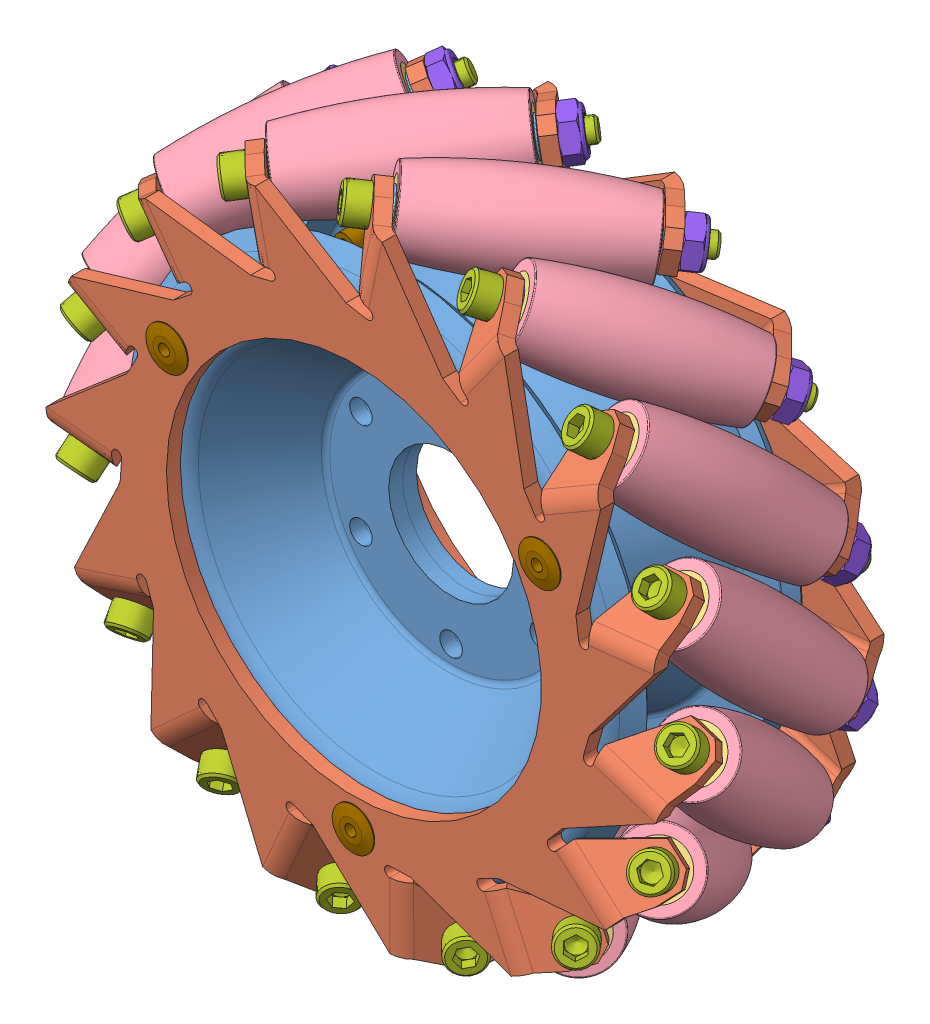
SolidWorks assembly am-3479L+6+SR+Mecanum+Left, configuration Default. Lengths in mm.
Overall size (158.3 158.04 52.39).
130 component instances, 9 part files, 0 mates.
Components (placement in the parent):
- ip-3479_hub-1: ip-3479_hub [Default] x (0 0 1) z (1 0 0) size (22.23 118.71 118.71)
- ip-3479_hub-2: ip-3479_hub [Default] x (0 0 -1) z (-1 0 0) size (22.23 118.71 118.71)
- am-0676a Left Plate HD-1: am-0676a Left Plate HD [Default] at (0 0 23.114) x (-0.999437 -0.033548 0) z (0 0 1) size (146.64 146.22 13.05)
- am-0676a Left Plate HD-2: am-0676a Left Plate HD [Default] at (0 0 -23.114) x (0.99946 -0.032864 0) z (0 0 -1) size (146.64 146.22 13.05)
- am-3479_roller-1: am-3479_roller [Default] at (-1.2868 -63.2825 -0.1615) x (-0.034273 0.998836 0.033931) z (0.706278 0.048228 -0.70629) size (19.48 44.35 19.48)
  - am-3698_core PC-1: am-3698_core PC [Default] at (-2.9239 1.0394 0.8367) size (14.92 43.18 14.92)
  - am-3698_skin TPU v2-1: am-3698_skin TPU v2 [Default] at (-2.9239 22.6294 0.8367) x (1 0 0) z (0 1 0) size (19.48 19.48 43.18)
  - am-0603 MBC Bushing MU04TH04-1: am-0603 MBC Bushing MU04TH04 [Default] at (-2.9239 -20.9316 0.8367) x (0 1 0) z (0 0 1) size (6.36 7.94 7.94)
  - am-0603 MBC Bushing MU04TH04-2: am-0603 MBC Bushing MU04TH04 [Default] at (-2.9239 16.6604 0.8367) x (0 1 0) z (-0.707574 0 0.70664) size (6.36 7.94 7.94)
  - am-0701a 6IN SR Roller Axle-1: am-0701a 6IN SR Roller Axle [Default] at (-2.9239 23.2136 0.8367) x (0 -1 0) z (0 0 1) size (44.35 6.35 6.35)
- 10-32x2250_shcs_HX-SHCS 0.19-32x1.375x1-C-1: 10-32x2250_shcs_HX-SHCS 0.19-32x1.375x1-C [Default] at (21.4977 -66.155 21.2417) x (-0.707105 -0.000242 -0.707109) z (0.143048 -0.979373 -0.142712) size (61.98 7.94 7.94)
- 10-32 Nylock Jam Nut_90633A411-1: 10-32 Nylock Jam Nut_90633A411 [Default] at (-17.791 -66.1685 -18.0472) x (0.176781 0.968184 -0.177112) z (-0.684654 0.25024 0.684564) size (9.53 4.55 11)
- 10-32 Nylock Jam Nut_90633A411-2: 10-32 Nylock Jam Nut_90633A411 [Default] at (-43.166 -53.2117 -18.0472) x (0.555294 0.812576 -0.177112) z (-0.523681 0.50708 0.684564) size (9.53 4.55 11)
- 10-32 Nylock Jam Nut_90633A411-3: 10-32 Nylock Jam Nut_90633A411 [Default] at (-61.0773 -31.0541 -18.0472) x (0.837791 0.516467 -0.177112) z (-0.272158 0.676241 0.684564) size (9.53 4.55 11)
- 10-32 Nylock Jam Nut_90633A411-4: 10-32 Nylock Jam Nut_90633A411 [Default] at (-68.4277 -3.527 -18.0472) x (0.975426 0.131056 -0.177112) z (0.026423 0.728473 0.684564) size (9.53 4.55 11)
- 10-32 Nylock Jam Nut_90633A411-5: 10-32 Nylock Jam Nut_90633A411 [Default] at (-63.9463 24.61 -18.0472) x (0.944401 -0.277016 -0.177112) z (0.320435 0.654747 0.684564) size (9.53 4.55 11)
- 10-32 Nylock Jam Nut_90633A411-6: 10-32 Nylock Jam Nut_90633A411 [Default] at (-48.4081 48.4917 -18.0472) x (0.750081 -0.637189 -0.177112) z (0.559041 0.467808 0.684564) size (9.53 4.55 11)
- 10-32 Nylock Jam Nut_90633A411-7: 10-32 Nylock Jam Nut_90633A411 [Default] at (-24.4997 63.9887 -18.0472) x (0.426065 -0.887187 -0.177112) z (0.700984 0.199981 0.684564) size (9.53 4.55 11)
- 10-32 Nylock Jam Nut_90633A411-8: 10-32 Nylock Jam Nut_90633A411 [Default] at (3.645 68.4215 -18.0472) x (0.028379 -0.983782 -0.177112) z (0.721721 -0.102424 0.684564) size (9.53 4.55 11)
- 10-32 Nylock Jam Nut_90633A411-9: 10-32 Nylock Jam Nut_90633A411 [Default] at (31.1594 61.0236 -18.0472) x (-0.374215 -0.910272 -0.177112) z (0.617665 -0.387119 0.684564) size (9.53 4.55 11)
- 10-32 Nylock Jam Nut_90633A411-10: 10-32 Nylock Jam Nut_90633A411 [Default] at (53.2861 43.0742 -18.0472) x (-0.712103 -0.679368 -0.177112) z (0.40681 -0.604878 0.684564) size (9.53 4.55 11)
- 10-32 Nylock Jam Nut_90633A411-11: 10-32 Nylock Jam Nut_90633A411 [Default] at (66.1991 17.6768 -18.0472) x (-0.926862 -0.330995 -0.177112) z (0.125613 -0.718048 0.684564) size (9.53 4.55 11)
- 10-32 Nylock Jam Nut_90633A411-12: 10-32 Nylock Jam Nut_90633A411 [Default] at (67.6657 -10.777 -18.0472) x (-0.981359 0.07461 -0.177112) z (-0.177303 -0.707061 0.684564) size (9.53 4.55 11)
- 10-32 Nylock Jam Nut_90633A411-13: 10-32 Nylock Jam Nut_90633A411 [Default] at (57.4323 -37.3674 -18.0472) x (-0.866169 0.467314 -0.177112) z (-0.449562 -0.573817 0.684564) size (9.53 4.55 11)
- 10-32 Nylock Jam Nut_90633A411-14: 10-32 Nylock Jam Nut_90633A411 [Default] at (37.2683 -57.4966 -18.0472) x (-0.601211 0.779216 -0.177112) z (-0.644088 -0.341354 0.684564) size (9.53 4.55 11)
- 10-32 Nylock Jam Nut_90633A411-15: 10-32 Nylock Jam Nut_90633A411 [Default] at (10.6603 -67.6842 -18.0472) x (-0.232298 0.956383 -0.177112) z (-0.727245 -0.049868 0.684564) size (9.53 4.55 11)
- 10-32x2250_shcs_HX-SHCS 0.19-32x1.375x1-C-2: 10-32x2250_shcs_HX-SHCS 0.19-32x1.375x1-C [Default] at (-7.2685 -69.1795 21.2417) x (-0.646071 0.287384 -0.707109) z (-0.267666 -0.952884 -0.142712) size (61.98 7.94 7.94)
- 10-32x2250_shcs_HX-SHCS 0.19-32x1.375x1-C-3: 10-32x2250_shcs_HX-SHCS 0.19-32x1.375x1-C [Default] at (-34.778 -60.2423 21.2417) x (-0.473325 0.525319 -0.707109) z (-0.632098 -0.761633 -0.142712) size (61.98 7.94 7.94)
- 10-32x2250_shcs_HX-SHCS 0.19-32x1.375x1-C-4: 10-32x2250_shcs_HX-SHCS 0.19-32x1.375x1-C [Default] at (-56.274 -40.8886 21.2417) x (-0.218738 0.672422 -0.707109) z (-0.887234 -0.438689 -0.142712) size (61.98 7.94 7.94)
- 10-32x2250_shcs_HX-SHCS 0.19-32x1.375x1-C-5: 10-32x2250_shcs_HX-SHCS 0.19-32x1.375x1-C [Default] at (-68.0398 -14.4649 21.2417) x (0.073672 0.703256 -0.707109) z (-0.98896 -0.039892 -0.142712) size (61.98 7.94 7.94)
- 10-32x2250_shcs_HX-SHCS 0.19-32x1.375x1-C-6: 10-32x2250_shcs_HX-SHCS 0.19-32x1.375x1-C [Default] at (-68.0408 14.4599 21.2417) x (0.353343 0.612492 -0.707109) z (-0.919685 0.365803 -0.142712) size (61.98 7.94 7.94)
- 10-32x2250_shcs_HX-SHCS 0.19-32x1.375x1-C-7: 10-32x2250_shcs_HX-SHCS 0.19-32x1.375x1-C [Default] at (-56.277 40.8845 21.2417) x (0.571917 0.415821 -0.707109) z (-0.691389 0.708248 -0.142712) size (61.98 7.94 7.94)
- 10-32x2250_shcs_HX-SHCS 0.19-32x1.375x1-C-8: 10-32x2250_shcs_HX-SHCS 0.19-32x1.375x1-C [Default] at (-34.7823 60.2398 21.2417) x (0.691602 0.147252 -0.707109) z (-0.343545 0.92823 -0.142712) size (61.98 7.94 7.94)
- 10-32x2250_shcs_HX-SHCS 0.19-32x1.375x1-C-9: 10-32x2250_shcs_HX-SHCS 0.19-32x1.375x1-C [Default] at (-7.2735 69.179 21.2417) x (0.691703 -0.146778 -0.707109) z (0.063701 0.987712 -0.142712) size (61.98 7.94 7.94)
- 10-32x2250_shcs_HX-SHCS 0.19-32x1.375x1-C-10: 10-32x2250_shcs_HX-SHCS 0.19-32x1.375x1-C [Default] at (21.4929 66.1566 21.2417) x (0.572202 -0.41543 -0.707109) z (0.459933 0.876411 -0.142712) size (61.98 7.94 7.94)
- 10-32x2250_shcs_HX-SHCS 0.19-32x1.375x1-C-11: 10-32x2250_shcs_HX-SHCS 0.19-32x1.375x1-C [Default] at (46.5431 51.6951 21.2417) x (0.353762 -0.612249 -0.707109) z (0.776638 0.613569 -0.142712) size (61.98 7.94 7.94)
- 10-32x2250_shcs_HX-SHCS 0.19-32x1.375x1-C-12: 10-32x2250_shcs_HX-SHCS 0.19-32x1.375x1-C [Default] at (63.5455 28.295 21.2417) x (0.074153 -0.703206 -0.707109) z (0.959055 0.244637 -0.142712) size (61.98 7.94 7.94)
- 10-32x2250_shcs_HX-SHCS 0.19-32x1.375x1-C-13: 10-32x2250_shcs_HX-SHCS 0.19-32x1.375x1-C [Default] at (69.5603 0.0025 21.2417) x (-0.218277 -0.672571 -0.707109) z (0.975643 -0.166596 -0.142712) size (61.98 7.94 7.94)
- 10-32x2250_shcs_HX-SHCS 0.19-32x1.375x1-C-14: 10-32x2250_shcs_HX-SHCS 0.19-32x1.375x1-C [Default] at (63.5476 -28.2904 21.2417) x (-0.472965 -0.525643 -0.707109) z (0.823533 -0.549023 -0.142712) size (61.98 7.94 7.94)
- 10-32x2250_shcs_HX-SHCS 0.19-32x1.375x1-C-15: 10-32x2250_shcs_HX-SHCS 0.19-32x1.375x1-C [Default] at (46.5468 -51.6917 21.2417) x (-0.645874 -0.287827 -0.707109) z (0.529027 -0.836519 -0.142712) size (61.98 7.94 7.94)
- am-3479_roller-2: am-3479_roller [Default] at (-26.9148 -57.288 -0.1615) x (0.374953 0.926423 0.033931) z (0.664833 -0.243211 -0.70629) size (19.48 44.35 19.48)
  - am-3698_core PC-1: am-3698_core PC [Default] at (-2.9239 1.0394 0.8367) size (14.92 43.18 14.92)
  - am-3698_skin TPU v2-1: am-3698_skin TPU v2 [Default] at (-2.9239 22.6294 0.8367) x (1 0 0) z (0 1 0) size (19.48 19.48 43.18)
  - am-0603 MBC Bushing MU04TH04-1: am-0603 MBC Bushing MU04TH04 [Default] at (-2.9239 -20.9316 0.8367) x (0 1 0) z (0 0 1) size (6.36 7.94 7.94)
  - am-0603 MBC Bushing MU04TH04-2: am-0603 MBC Bushing MU04TH04 [Default] at (-2.9239 16.6604 0.8367) x (0 1 0) z (-0.707574 0 0.70664) size (6.36 7.94 7.94)
  - am-0701a 6IN SR Roller Axle-1: am-0701a 6IN SR Roller Axle [Default] at (-2.9239 23.2136 0.8367) x (0 -1 0) z (0 0 1) size (44.35 6.35 6.35)
- am-3479_roller-3: am-3479_roller [Default] at (-47.889 -41.388 -0.1615) x (0.719347 0.693822 0.033931) z (0.508432 -0.492596 -0.70629) size (19.48 44.35 19.48)
  - am-3698_core PC-1: am-3698_core PC [Default] at (-2.9239 1.0394 0.8367) size (14.92 43.18 14.92)
  - am-3698_skin TPU v2-1: am-3698_skin TPU v2 [Default] at (-2.9239 22.6294 0.8367) x (1 0 0) z (0 1 0) size (19.48 19.48 43.18)
  - am-0603 MBC Bushing MU04TH04-1: am-0603 MBC Bushing MU04TH04 [Default] at (-2.9239 -20.9316 0.8367) x (0 1 0) z (0 0 1) size (6.36 7.94 7.94)
  - am-0603 MBC Bushing MU04TH04-2: am-0603 MBC Bushing MU04TH04 [Default] at (-2.9239 16.6604 0.8367) x (0 1 0) z (-0.707574 0 0.70664) size (6.36 7.94 7.94)
  - am-0701a 6IN SR Roller Axle-1: am-0701a 6IN SR Roller Axle [Default] at (-2.9239 23.2136 0.8367) x (0 -1 0) z (0 0 1) size (44.35 6.35 6.35)
- am-3479_roller-4: am-3479_roller [Default] at (-60.5828 -18.3316 -0.1615) x (0.939359 0.341253 0.033931) z (0.264119 -0.656807 -0.70629) size (19.48 44.35 19.48)
  - am-3698_core PC-1: am-3698_core PC [Default] at (-2.9239 1.0394 0.8367) size (14.92 43.18 14.92)
  - am-3698_skin TPU v2-1: am-3698_skin TPU v2 [Default] at (-2.9239 22.6294 0.8367) x (1 0 0) z (0 1 0) size (19.48 19.48 43.18)
  - am-0603 MBC Bushing MU04TH04-1: am-0603 MBC Bushing MU04TH04 [Default] at (-2.9239 -20.9316 0.8367) x (0 1 0) z (0 0 1) size (6.36 7.94 7.94)
  - am-0603 MBC Bushing MU04TH04-2: am-0603 MBC Bushing MU04TH04 [Default] at (-2.9239 16.6604 0.8367) x (0 1 0) z (-0.707574 0 0.70664) size (6.36 7.94 7.94)
  - am-0701a 6IN SR Roller Axle-1: am-0701a 6IN SR Roller Axle [Default] at (-2.9239 23.2136 0.8367) x (0 -1 0) z (0 0 1) size (44.35 6.35 6.35)
- am-3479_roller-5: am-3479_roller [Default] at (-62.8013 7.8945 -0.1615) x (0.996947 -0.070321 0.033931) z (-0.025863 -0.70745 -0.70629) size (19.48 44.35 19.48)
  - am-3698_core PC-1: am-3698_core PC [Default] at (-2.9239 1.0394 0.8367) size (14.92 43.18 14.92)
  - am-3698_skin TPU v2-1: am-3698_skin TPU v2 [Default] at (-2.9239 22.6294 0.8367) x (1 0 0) z (0 1 0) size (19.48 19.48 43.18)
  - am-0603 MBC Bushing MU04TH04-1: am-0603 MBC Bushing MU04TH04 [Default] at (-2.9239 -20.9316 0.8367) x (0 1 0) z (0 0 1) size (6.36 7.94 7.94)
  - am-0603 MBC Bushing MU04TH04-2: am-0603 MBC Bushing MU04TH04 [Default] at (-2.9239 16.6604 0.8367) x (0 1 0) z (-0.707574 0 0.70664) size (6.36 7.94 7.94)
  - am-0701a 6IN SR Roller Axle-1: am-0701a 6IN SR Roller Axle [Default] at (-2.9239 23.2136 0.8367) x (0 -1 0) z (0 0 1) size (44.35 6.35 6.35)
- am-3479_roller-6: am-3479_roller [Default] at (-54.1608 32.7556 -0.1615) x (0.882154 -0.469737 0.033931) z (-0.311373 -0.635768 -0.70629) size (19.48 44.35 19.48)
  - am-3698_core PC-1: am-3698_core PC [Default] at (-2.9239 1.0394 0.8367) size (14.92 43.18 14.92)
  - am-3698_skin TPU v2-1: am-3698_skin TPU v2 [Default] at (-2.9239 22.6294 0.8367) x (1 0 0) z (0 1 0) size (19.48 19.48 43.18)
  - am-0603 MBC Bushing MU04TH04-1: am-0603 MBC Bushing MU04TH04 [Default] at (-2.9239 -20.9316 0.8367) x (0 1 0) z (0 0 1) size (6.36 7.94 7.94)
  - am-0603 MBC Bushing MU04TH04-2: am-0603 MBC Bushing MU04TH04 [Default] at (-2.9239 16.6604 0.8367) x (0 1 0) z (-0.707574 0 0.70664) size (6.36 7.94 7.94)
  - am-0701a 6IN SR Roller Axle-1: am-0701a 6IN SR Roller Axle [Default] at (-2.9239 23.2136 0.8367) x (0 -1 0) z (0 0 1) size (44.35 6.35 6.35)
- am-3479_roller-7: am-3479_roller [Default] at (-36.1555 51.9529 -0.1615) x (0.614829 -0.78793 0.033931) z (-0.543043 -0.454157 -0.70629) size (19.48 44.35 19.48)
  - am-3698_core PC-1: am-3698_core PC [Default] at (-2.9239 1.0394 0.8367) size (14.92 43.18 14.92)
  - am-3698_skin TPU v2-1: am-3698_skin TPU v2 [Default] at (-2.9239 22.6294 0.8367) x (1 0 0) z (0 1 0) size (19.48 19.48 43.18)
  - am-0603 MBC Bushing MU04TH04-1: am-0603 MBC Bushing MU04TH04 [Default] at (-2.9239 -20.9316 0.8367) x (0 1 0) z (0 0 1) size (6.36 7.94 7.94)
  - am-0603 MBC Bushing MU04TH04-2: am-0603 MBC Bushing MU04TH04 [Default] at (-2.9239 16.6604 0.8367) x (0 1 0) z (-0.707574 0 0.70664) size (6.36 7.94 7.94)
  - am-0701a 6IN SR Roller Axle-1: am-0701a 6IN SR Roller Axle [Default] at (-2.9239 23.2136 0.8367) x (0 -1 0) z (0 0 1) size (44.35 6.35 6.35)
- am-3479_roller-8: am-3479_roller [Default] at (-11.8985 62.1671 -0.1615) x (0.241194 -0.969884 0.033931) z (-0.680817 -0.194017 -0.70629) size (19.48 44.35 19.48)
  - am-3698_core PC-1: am-3698_core PC [Default] at (-2.9239 1.0394 0.8367) size (14.92 43.18 14.92)
  - am-3698_skin TPU v2-1: am-3698_skin TPU v2 [Default] at (-2.9239 22.6294 0.8367) x (1 0 0) z (0 1 0) size (19.48 19.48 43.18)
  - am-0603 MBC Bushing MU04TH04-1: am-0603 MBC Bushing MU04TH04 [Default] at (-2.9239 -20.9316 0.8367) x (0 1 0) z (0 0 1) size (6.36 7.94 7.94)
  - am-0603 MBC Bushing MU04TH04-2: am-0603 MBC Bushing MU04TH04 [Default] at (-2.9239 16.6604 0.8367) x (0 1 0) z (-0.707574 0 0.70664) size (6.36 7.94 7.94)
  - am-0701a 6IN SR Roller Axle-1: am-0701a 6IN SR Roller Axle [Default] at (-2.9239 23.2136 0.8367) x (0 -1 0) z (0 0 1) size (44.35 6.35 6.35)
- am-3479_roller-9: am-3479_roller [Default] at (14.4158 61.6321 -0.1615) x (-0.174146 -0.984135 0.033931) z (-0.700871 0.09967 -0.70629) size (19.48 44.35 19.48)
  - am-3698_core PC-1: am-3698_core PC [Default] at (-2.9239 1.0394 0.8367) size (14.92 43.18 14.92)
  - am-3698_skin TPU v2-1: am-3698_skin TPU v2 [Default] at (-2.9239 22.6294 0.8367) x (1 0 0) z (0 1 0) size (19.48 19.48 43.18)
  - am-0603 MBC Bushing MU04TH04-1: am-0603 MBC Bushing MU04TH04 [Default] at (-2.9239 -20.9316 0.8367) x (0 1 0) z (0 0 1) size (6.36 7.94 7.94)
  - am-0603 MBC Bushing MU04TH04-2: am-0603 MBC Bushing MU04TH04 [Default] at (-2.9239 16.6604 0.8367) x (0 1 0) z (-0.707574 0 0.70664) size (6.36 7.94 7.94)
  - am-0701a 6IN SR Roller Axle-1: am-0701a 6IN SR Roller Axle [Default] at (-2.9239 23.2136 0.8367) x (0 -1 0) z (0 0 1) size (44.35 6.35 6.35)
- am-3479_roller-10: am-3479_roller [Default] at (38.2375 50.4403 -0.1615) x (-0.559374 -0.828221 0.033931) z (-0.599738 0.376123 -0.70629) size (19.48 44.35 19.48)
  - am-3698_core PC-1: am-3698_core PC [Default] at (-2.9239 1.0394 0.8367) size (14.92 43.18 14.92)
  - am-3698_skin TPU v2-1: am-3698_skin TPU v2 [Default] at (-2.9239 22.6294 0.8367) x (1 0 0) z (0 1 0) size (19.48 19.48 43.18)
  - am-0603 MBC Bushing MU04TH04-1: am-0603 MBC Bushing MU04TH04 [Default] at (-2.9239 -20.9316 0.8367) x (0 1 0) z (0 0 1) size (6.36 7.94 7.94)
  - am-0603 MBC Bushing MU04TH04-2: am-0603 MBC Bushing MU04TH04 [Default] at (-2.9239 16.6604 0.8367) x (0 1 0) z (-0.707574 0 0.70664) size (6.36 7.94 7.94)
  - am-0701a 6IN SR Roller Axle-1: am-0701a 6IN SR Roller Axle [Default] at (-2.9239 23.2136 0.8367) x (0 -1 0) z (0 0 1) size (44.35 6.35 6.35)
- am-3479_roller-11: am-3479_roller [Default] at (55.4476 30.5269 -0.1615) x (-0.847881 -0.5291 0.033931) z (-0.394905 0.587541 -0.70629) size (19.48 44.35 19.48)
  - am-3698_core PC-1: am-3698_core PC [Default] at (-2.9239 1.0394 0.8367) size (14.92 43.18 14.92)
  - am-3698_skin TPU v2-1: am-3698_skin TPU v2 [Default] at (-2.9239 22.6294 0.8367) x (1 0 0) z (0 1 0) size (19.48 19.48 43.18)
  - am-0603 MBC Bushing MU04TH04-1: am-0603 MBC Bushing MU04TH04 [Default] at (-2.9239 -20.9316 0.8367) x (0 1 0) z (0 0 1) size (6.36 7.94 7.94)
  - am-0603 MBC Bushing MU04TH04-2: am-0603 MBC Bushing MU04TH04 [Default] at (-2.9239 16.6604 0.8367) x (0 1 0) z (-0.707574 0 0.70664) size (6.36 7.94 7.94)
  - am-0701a 6IN SR Roller Axle-1: am-0701a 6IN SR Roller Axle [Default] at (-2.9239 23.2136 0.8367) x (0 -1 0) z (0 0 1) size (44.35 6.35 6.35)
- am-3479_roller-12: am-3479_roller [Default] at (63.0703 5.3351 -0.1615) x (-0.989782 -0.138492 0.033931) z (-0.121789 0.697368 -0.70629) size (19.48 44.35 19.48)
  - am-3698_core PC-1: am-3698_core PC [Default] at (-2.9239 1.0394 0.8367) size (14.92 43.18 14.92)
  - am-3698_skin TPU v2-1: am-3698_skin TPU v2 [Default] at (-2.9239 22.6294 0.8367) x (1 0 0) z (0 1 0) size (19.48 19.48 43.18)
  - am-0603 MBC Bushing MU04TH04-1: am-0603 MBC Bushing MU04TH04 [Default] at (-2.9239 -20.9316 0.8367) x (0 1 0) z (0 0 1) size (6.36 7.94 7.94)
  - am-0603 MBC Bushing MU04TH04-2: am-0603 MBC Bushing MU04TH04 [Default] at (-2.9239 16.6604 0.8367) x (0 1 0) z (-0.707574 0 0.70664) size (6.36 7.94 7.94)
  - am-0701a 6IN SR Roller Axle-1: am-0701a 6IN SR Roller Axle [Default] at (-2.9239 23.2136 0.8367) x (0 -1 0) z (0 0 1) size (44.35 6.35 6.35)
- am-3479_roller-13: am-3479_roller [Default] at (59.7876 -20.7791 -0.1615) x (-0.960541 0.276062 0.033931) z (0.172385 0.686613 -0.70629) size (19.48 44.35 19.48)
  - am-3698_core PC-1: am-3698_core PC [Default] at (-2.9239 1.0394 0.8367) size (14.92 43.18 14.92)
  - am-3698_skin TPU v2-1: am-3698_skin TPU v2 [Default] at (-2.9239 22.6294 0.8367) x (1 0 0) z (0 1 0) size (19.48 19.48 43.18)
  - am-0603 MBC Bushing MU04TH04-1: am-0603 MBC Bushing MU04TH04 [Default] at (-2.9239 -20.9316 0.8367) x (0 1 0) z (0 0 1) size (6.36 7.94 7.94)
  - am-0603 MBC Bushing MU04TH04-2: am-0603 MBC Bushing MU04TH04 [Default] at (-2.9239 16.6604 0.8367) x (0 1 0) z (-0.707574 0 0.70664) size (6.36 7.94 7.94)
  - am-0701a 6IN SR Roller Axle-1: am-0701a 6IN SR Roller Axle [Default] at (-2.9239 23.2136 0.8367) x (0 -1 0) z (0 0 1) size (44.35 6.35 6.35)
- am-3479_roller-14: am-3479_roller [Default] at (46.167 -43.3005 -0.1615) x (-0.765213 0.642882 0.033931) z (0.436752 0.557137 -0.70629) size (19.48 44.35 19.48)
  - am-3698_core PC-1: am-3698_core PC [Default] at (-2.9239 1.0394 0.8367) size (14.92 43.18 14.92)
  - am-3698_skin TPU v2-1: am-3698_skin TPU v2 [Default] at (-2.9239 22.6294 0.8367) x (1 0 0) z (0 1 0) size (19.48 19.48 43.18)
  - am-0603 MBC Bushing MU04TH04-1: am-0603 MBC Bushing MU04TH04 [Default] at (-2.9239 -20.9316 0.8367) x (0 1 0) z (0 0 1) size (6.36 7.94 7.94)
  - am-0603 MBC Bushing MU04TH04-2: am-0603 MBC Bushing MU04TH04 [Default] at (-2.9239 16.6604 0.8367) x (0 1 0) z (-0.707574 0 0.70664) size (6.36 7.94 7.94)
  - am-0701a 6IN SR Roller Axle-1: am-0701a 6IN SR Roller Axle [Default] at (-2.9239 23.2136 0.8367) x (0 -1 0) z (0 0 1) size (44.35 6.35 6.35)
- am-3479_roller-15: am-3479_roller [Default] at (24.5638 -58.3348 -0.1615) x (-0.437573 0.898542 0.033931) z (0.625601 0.331327 -0.70629) size (19.48 44.35 19.48)
  - am-3698_core PC-1: am-3698_core PC [Default] at (-2.9239 1.0394 0.8367) size (14.92 43.18 14.92)
  - am-3698_skin TPU v2-1: am-3698_skin TPU v2 [Default] at (-2.9239 22.6294 0.8367) x (1 0 0) z (0 1 0) size (19.48 19.48 43.18)
  - am-0603 MBC Bushing MU04TH04-1: am-0603 MBC Bushing MU04TH04 [Default] at (-2.9239 -20.9316 0.8367) x (0 1 0) z (0 0 1) size (6.36 7.94 7.94)
  - am-0603 MBC Bushing MU04TH04-2: am-0603 MBC Bushing MU04TH04 [Default] at (-2.9239 16.6604 0.8367) x (0 1 0) z (-0.707574 0 0.70664) size (6.36 7.94 7.94)
  - am-0701a 6IN SR Roller Axle-1: am-0701a 6IN SR Roller Axle [Default] at (-2.9239 23.2136 0.8367) x (0 -1 0) z (0 0 1) size (44.35 6.35 6.35)
- am-1226 steel rivet 1875 125-250 grip-1: am-1226 steel rivet 1875 125-250 grip [Default] at (0.0337 -49.2125 -15.0812) x (0.985757 0.168176 0) z (-0.168176 0.985757 0) size (9.53 11.11 9.53)
- am-1226 steel rivet 1875 125-250 grip-2: am-1226 steel rivet 1875 125-250 grip [Default] at (-42.6193 24.6062 -15.0812) x (-0.99171 0.128499 0) z (-0.128499 -0.99171 0) size (9.53 11.11 9.53)
- am-1226 steel rivet 1875 125-250 grip-3: am-1226 steel rivet 1875 125-250 grip [Default] at (42.6024 24.6354 -15.0812) x (0.892255 0.451532 0) z (-0.451532 0.892255 0) size (9.53 11.11 9.53)
- am-1226 steel rivet 1875 125-250 grip-4: am-1226 steel rivet 1875 125-250 grip [Default] at (42.6193 24.6062 15.0812) x (0.934139 0.35691 0) z (0.35691 -0.934139 0) size (9.53 11.11 9.53)
- am-1226 steel rivet 1875 125-250 grip-5: am-1226 steel rivet 1875 125-250 grip [Default] at (-42.6193 24.6062 15.0812) x (-0.689528 -0.724259 0) z (-0.724259 0.689528 0) size (9.53 11.11 9.53)
- am-1226 steel rivet 1875 125-250 grip-6: am-1226 steel rivet 1875 125-250 grip [Default] at (0 -49.2125 15.0812) x (-0.060828 0.998148 0) z (0.998148 0.060828 0) size (9.53 11.11 9.53)
